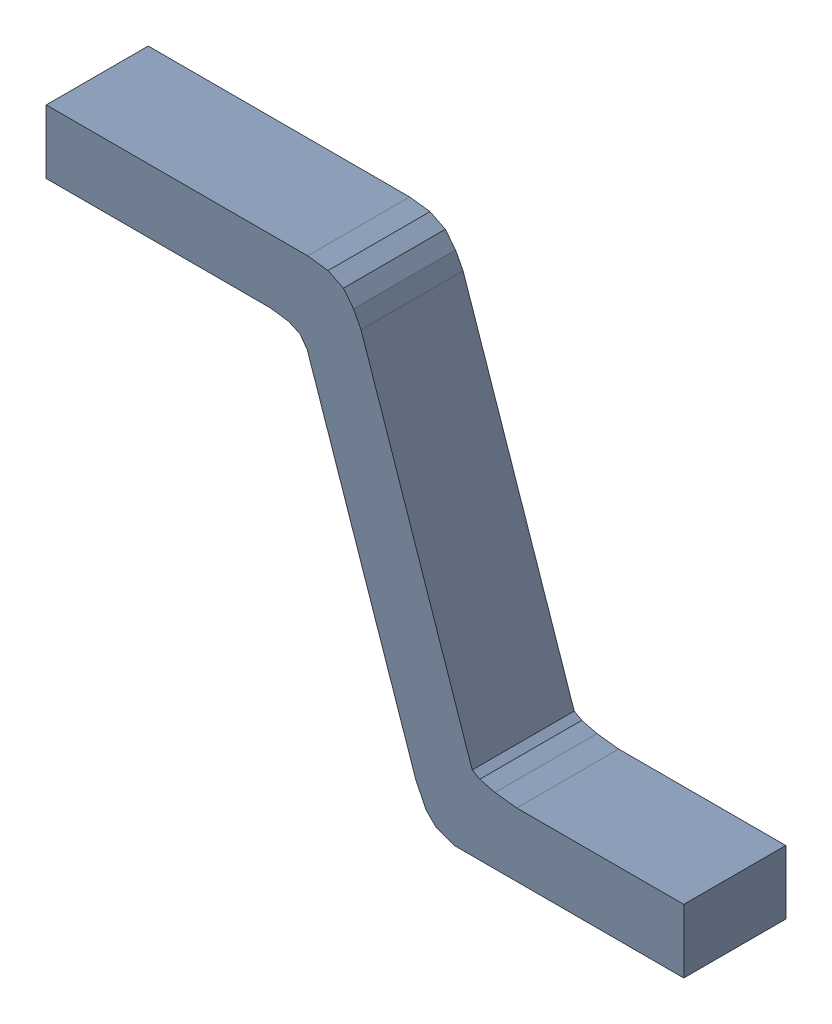
SolidWorks assembly SW3dPS-TO263-3S_Free-Models6, configuration Default. Lengths in mm.
Overall size (5 3.43 0.8).
2 component instances, 1 part files, 0 mates.
Components (placement in the parent):
- SW3dPS-TO263-3S_453496145-1: SW3dPS-TO263-3S_453496145 [Default] at (-2.4 1.465 -0.3873) size (5 3.43 0.8)
  - SW3dPS-TO263-3S_Extruded13-1: SW3dPS-TO263-3S_Extruded13 [Default] at origin size (5 3.43 0.8)
